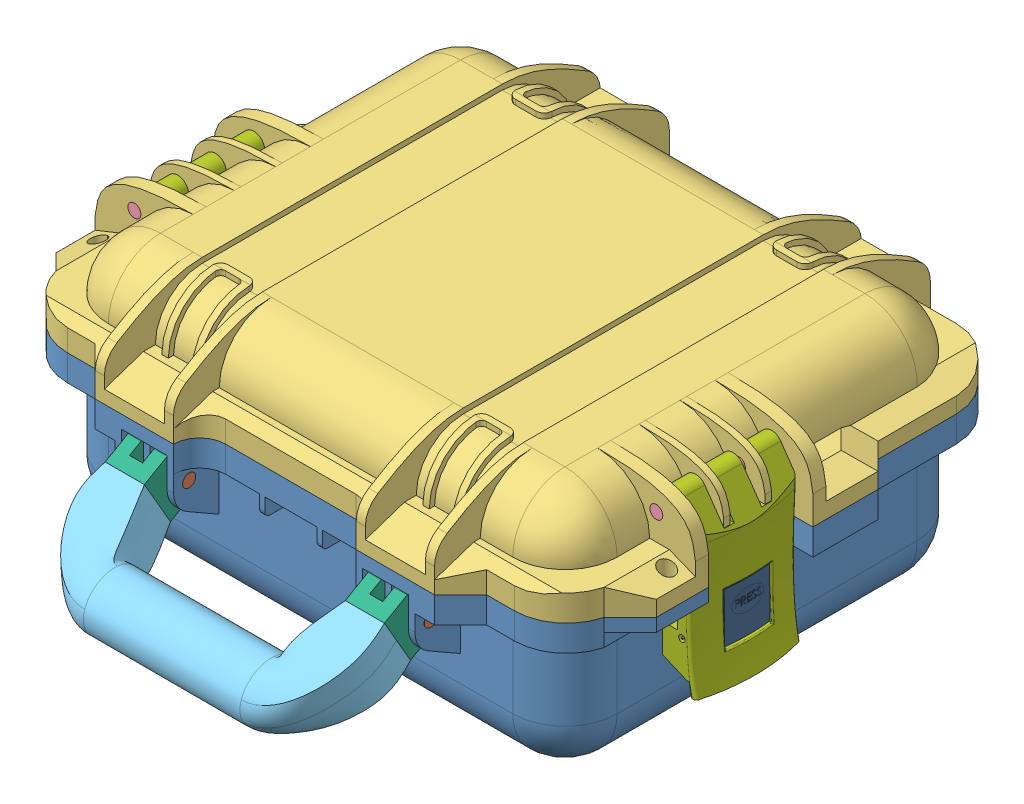
SolidWorks assembly Pelican Storm Case iM2050, configuration Default. Lengths in mm.
Overall size (292.1 116.84 296.9).
22 component instances, 10 part files, 8 mates.
Components (placement in the parent):
- container-1: container [Default] at origin size (292.1 85.09 238.13)
  - container main-1: container main [Default] at origin size (292.1 85.09 238.13)
  - front handle pin-1: front handle pin [Default] at (-58.801 -6.35 113.03) size (28.7 6.35 6.35)
  - front handle pin-2: front handle pin [Default] at (58.801 -6.35 113.03) size (28.7 6.35 6.35)
- cover-1: cover [Default] at (0 25.4 0) size (292.1 38.1 241.3)
  - cover main-1: cover main [Default] at origin size (292.1 38.1 241.3)
  - latch pin-1: latch pin [Default] at (127 12.7 25.4) x (0 0 -1) z (1 0 0) size (63.5 6.35 6.35)
  - latch pin-2: latch pin [Default] at (-127 12.7 25.4) x (0 0 -1) z (1 0 0) size (63.5 6.35 6.35)
- handle-1: handle [Default] at (0 -31.75 157.0241) x (1 0 0) z (0 -0.5 0.866025) size (143.22 27.25 77.84)
  - handle grip-1: handle grip [Default] at origin size (143.22 27.25 52.45)
  - handle mount-1: handle mount [Default] at (58.42 0 -38.1) x (1 0 0) z (0 -1 0) size (19.05 25.4 25.4)
  - handle mount-2: handle mount [Default] at (-58.42 0 -38.1) x (1 0 0) z (0 -1 0) size (19.05 25.4 25.4)
- side latch-1: side latch [Default] at (139.9027 25.2835 25.4595) x (0 0 -1) z (0.99996 -0.008992 0) size (51.15 81.59 23.77)
  - side latch main-1: side latch main [Default] at origin size (51.15 81.59 23.77)
  - side latch button pin-1: side latch button pin [Default] at (0 -40.64 -6.35) size (50.8 3.17 3.17)
  - side latch button spring-1: side latch button spring [Default] at (3.1752 -40.64 -6.35) x (1 0 0) z (0 -0.978148 0.207912) size (7.25 8.76 24.29)
  - side latch button-1: side latch button [Default] at (0 -36.0898 -0.075) x (1 0 0) z (0 -0.999861 0.016664) size (22.1 17.14 31.12)
- side latch-2: side latch [Default] at (-140.0175 25.4 25.3055) x (0 0 1) z (-1 0 0) size (51.15 81.59 23.77)
  - side latch main-1: side latch main [Default] at origin size (51.15 81.59 23.77)
  - side latch button pin-1: side latch button pin [Default] at (0 -40.64 -6.35) size (50.8 3.17 3.17)
  - side latch button spring-1: side latch button spring [Default] at (3.1752 -40.64 -6.35) x (1 0 0) z (0 -0.978148 0.207912) size (7.25 8.76 24.29)
  - side latch button-1: side latch button [Default] at (0 -36.0898 -0.075) x (1 0 0) z (0 -0.999861 0.016664) size (22.1 17.14 31.12)
Mates (geometry in assembly coordinates):
- Coincident1: coincident: plane of container-1/container main-1 through (0 0 0) normal (0 0 1); plane of cover-1/cover main-1 through (0 25.4 0) normal (0 0 1)
- Coincident2: coincident: plane of container-1/container main-1 through (0 0 0) normal (1 0 0); plane of cover-1/cover main-1 through (0 25.4 0) normal (1 0 0)
- Coincident3: coincident: axis of container-1/front handle pin-1 through (-44.45 -6.35 113.03) axis (-1 0 0); axis of handle-1/handle mount-2 through (-61.595 -6.35 113.03) axis (-1 0 0)
- Distance1: distance = 1.27 mm: plane of handle-1/handle mount-2 through (-61.595 10.9985 108.3815) normal (1 0 0); plane of container-1/container main-1 through (-60.325 -15.24 146.2477) normal (-1 0 0)
- Angle1: planar angle = 0.523599 rad: plane of handle-1/handle grip-1 through (0 -31.75 157.0241) normal (0 0.866025 0.5); plane of container-1/container main-1 through (0 0 0) normal (0 1 0)
- Concentric1: concentric: cylinder of cover-1/latch pin-1 through (127 38.1 -6.35) axis (0 0 1) radius 3.175; cylinder of side latch-1/side latch main-1 through (127 38.1 51.055) axis (0 0 -1) radius 3.175
- Concentric2: concentric: cylinder of cover-1/latch pin-2 through (-127 38.1 -6.35) axis (0 0 1) radius 3.175; cylinder of side latch-2/side latch main-1 through (-127 38.1 -0.29) axis (0 0 1) radius 3.175
- Coincident4: coincident: plane of container-1/container main-1 through (-44.45 12.7 120.65) normal (0 1 0); plane of cover-1/cover main-1 through (-44.45 12.7 120.65) normal (0 -1 0)
